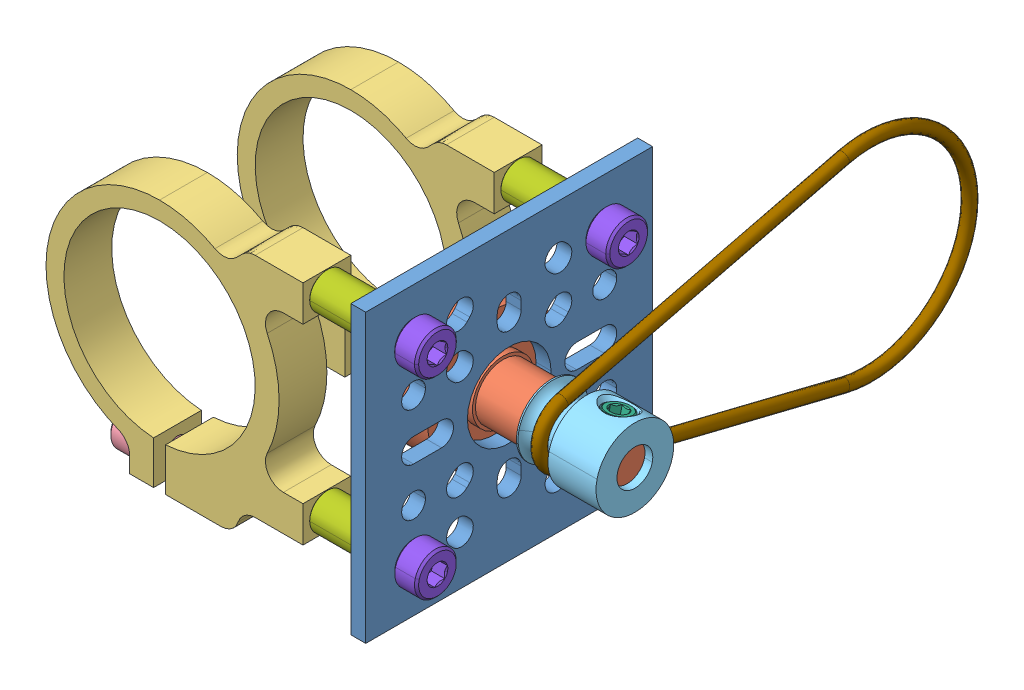
SolidWorks assembly Encoder2_Assembly, configuration Default. Lengths in mm.
Overall size (78.53 48 92).
23 component instances, 9 part files, 32 mates.
Components (placement in the parent):
- 1123-0048-0048-1: 1123-0048-0048 [Default] at (18.41 -24 21.5) size (2.5 48 48)
- 6127V1A360L.5 Non-Contacting Hall Effect-1: 6127V1A360L.5 Non-Contacting Hall Effect [Default] at origin size (35.77 22.23 22.23)
- 1400-0032-0032 assembly-1: 1400-0032-0032 assembly [Default] at (-32.0342 -9.2052 15.0483) x (0 -1 0) z (0 0 -1) size (42.19 43 8)
  - 1400-0032-0032 assembly.STEP-1: 1400-0032-0032 assembly.STEP [Default] at origin size (42.19 43 8)
    - 1400-0032-0032.STEP-1: 1400-0032-0032.STEP [Default] at (-9.2052 9.5558 -4.9517) size (42.17 43 8)
    - 2800-0004-0012_90128A207.STEP-1: 2800-0004-0012_90128A207.STEP [Default] at (10.4635 2.5558 -0.9517) x (0.999977 0 0.006769) z (0 -1 0) size (7 7 16.01)
- 1400-0032-0032 assembly-2: 1400-0032-0032 assembly [Default] at (-32.0342 -9.2052 -16.9517) x (0 -1 0) z (0 0 -1) size (42.19 43 8)
  - 1400-0032-0032 assembly.STEP-1: 1400-0032-0032 assembly.STEP [Default] at origin size (42.19 43 8)
    - 1400-0032-0032.STEP-1: 1400-0032-0032.STEP [Default] at (-9.2052 9.5558 -4.9517) size (42.17 43 8)
    - 2800-0004-0012_90128A207.STEP-1: 2800-0004-0012_90128A207.STEP [Default] at (10.4635 2.5558 -0.9517) x (0.999977 0 0.006769) z (0 -1 0) size (7 7 16.01)
- 3401-0006-0008 assembly-1: 3401-0006-0008 assembly [Default] at (9.8045 -37.374 -32.0723) x (0 -0.226049 -0.974116) z (1 0 0) size (13 13.01 14)
  - 3401-0006-0008 assembly.STEP-1: 3401-0006-0008 assembly.STEP [Default] at origin size (13 13.01 14)
    - 3401-0006-0008.STEP-1: 3401-0006-0008.STEP [Default] at (-39.6905 29.1567 8.1355) size (13 13.01 14)
    - 2806-0005-0004_91390A117.STEP-1: 2806-0005-0004_91390A117.STEP [Default] at (-39.6905 33.4996 4.1145) x (0.999377 0 0.035289) z (0 1 0) size (5.01 5.01 4.01)
- 1502-0006-0120-1: 1502-0006-0120 [Default] at (-11.59 16 16) x (0 1 0) z (0 0 1) size (5.95 12 5.95)
- 1502-0006-0120-2: 1502-0006-0120 [Default] at (-11.59 16 -16) x (0 1 0) z (0 0 1) size (5.95 12 5.95)
- 1502-0006-0120-3: 1502-0006-0120 [Default] at (-11.59 -16 16) x (0 1 0) z (0 0 1) size (5.95 12 5.95)
- 1502-0006-0120-4: 1502-0006-0120 [Default] at (-11.59 -16 -16) x (0 1 0) z (0 0 1) size (5.95 12 5.95)
- 2800-0004-0018-1: 2800-0004-0018 [Default] at (-21.09 16 16) x (0 0 1) z (-1 0 0) size (7 7 22.01)
- 2800-0004-0018-2: 2800-0004-0018 [Default] at (-21.09 -16 16) x (0 0.259369 0.965778) z (-1 0 0) size (7 7 22.01)
- 2800-0004-0018-3: 2800-0004-0018 [Default] at (-21.09 -16 -16) x (0 0 1) z (-1 0 0) size (7 7 22.01)
- 2800-0004-0018-4: 2800-0004-0018 [Default] at (-21.09 16 -16) x (0 0 1) z (-1 0 0) size (7 7 22.01)
- Round_Belt-1: Round_Belt [Default] at (6.94 0 0) x (0 0 -1) z (1 0 0) size (74 36 2)
Mates (geometry in assembly coordinates):
- Coincident2: coincident aligned: plane of 6127V1A360L.5 Non-Contacting Hall Effect-1 through (0 0 0) normal (0 0 1)
- Coincident3: coincident aligned: plane of 6127V1A360L.5 Non-Contacting Hall Effect-1 through (0 0 0) normal (0 1 0)
- Coincident4: coincident aligned: plane of 6127V1A360L.5 Non-Contacting Hall Effect-1 through (0 0 0) normal (1 0 0)
- Concentric1: concentric aligned: cylinder of 1123-0048-0048-1 through (4.41 0 0) axis (-1 0 0) radius 7; cylinder of 6127V1A360L.5 Non-Contacting Hall Effect-1 through (-16.64 0 0) axis (-1 0 0) radius 3.175
- Coincident5: coincident anti-aligned: plane of 1123-0048-0048-1 through (-5.59 24 -24) normal (-1 0 0); plane of 6127V1A360L.5 Non-Contacting Hall Effect-1 through (-5.59 11.115 0) normal (1 0 0)
- Parallel1: parallel aligned: plane of 1123-0048-0048-1 through (42.41 24 24) normal (0 0 1); plane of 1400-0032-0032 assembly-1/1400-0032-0032 assembly.STEP-1/1400-0032-0032.STEP-1 through (-41.59 0 20) normal (0 0 1)
- Parallel2: parallel aligned: plane of 1123-0048-0048-1 through (18.41 24 21.5) normal (0 1 0)
- Coincident9: coincident aligned: cylinder of 1123-0048-0048-1 through (4.41 16 16) axis (-1 0 0) radius 2; circle of 1400-0032-0032 assembly-1/1400-0032-0032 assembly.STEP-1/1400-0032-0032.STEP-1
- Distance1: distance = 12 mm anti-aligned: plane of 1123-0048-0048-1 through (-5.59 24 -24) normal (-1 0 0); plane of 1400-0032-0032 assembly-1/1400-0032-0032 assembly.STEP-1/1400-0032-0032.STEP-1 through (-17.59 13 12) normal (1 0 0)
- Concentric2: concentric aligned: cylinder of 1400-0032-0032 assembly-1/1400-0032-0032 assembly.STEP-1/1400-0032-0032.STEP-1 through (-41.59 0 12) axis (0 0 1) radius 16; cylinder of 1400-0032-0032 assembly-2/1400-0032-0032 assembly.STEP-1/1400-0032-0032.STEP-1 through (-41.59 0 -20) axis (0 0 1) radius 16
- Coincident11: coincident aligned: cylinder of 1123-0048-0048-1 through (4.41 16 -16) axis (-1 0 0) radius 2; circle of 1400-0032-0032 assembly-2/1400-0032-0032 assembly.STEP-1/1400-0032-0032.STEP-1
- Concentric3: concentric anti-aligned: cylinder of 6127V1A360L.5 Non-Contacting Hall Effect-1 through (-16.64 0 0) axis (-1 0 0) radius 3.175; cylinder of 3401-0006-0008 assembly-1/3401-0006-0008 assembly.STEP-1/3401-0006-0008.STEP-1 through (17.94 0 0) axis (1 0 0) radius 3
- Coincident12: coincident anti-aligned: plane of 6127V1A360L.5 Non-Contacting Hall Effect-1 through (3.94 3.175 0) normal (1 0 0); plane of 3401-0006-0008 assembly-1/3401-0006-0008 assembly.STEP-1/3401-0006-0008.STEP-1 through (3.94 0 0) normal (-1 0 0)
- Concentric4: concentric anti-aligned: cylinder of 1123-0048-0048-1 through (4.41 16 16) axis (-1 0 0) radius 2; cylinder of 1502-0006-0120-1 through (-17.59 16 16) axis (1 0 0) radius 2.975
- Concentric5: concentric anti-aligned: cylinder of 1123-0048-0048-1 through (4.41 16 -16) axis (-1 0 0) radius 2; cylinder of 1502-0006-0120-2 through (-17.59 16 -16) axis (1 0 0) radius 2.975
- Concentric6: concentric anti-aligned: cylinder of 1123-0048-0048-1 through (4.41 -16 -16) axis (-1 0 0) radius 2; cylinder of 1502-0006-0120-4 through (-17.59 -16 -16) axis (1 0 0) radius 2.975
- Concentric7: concentric anti-aligned: cylinder of 1123-0048-0048-1 through (4.41 -16 16) axis (-1 0 0) radius 2; cylinder of 1502-0006-0120-3 through (-17.59 -16 16) axis (1 0 0) radius 2.975
- Coincident13: coincident anti-aligned: plane of 1123-0048-0048-1 through (-5.59 24 -24) normal (-1 0 0); plane of 1502-0006-0120-1 through (-5.59 16 16) normal (1 0 0)
- Coincident14: coincident anti-aligned: plane of 1123-0048-0048-1 through (-5.59 24 -24) normal (-1 0 0); plane of 1502-0006-0120-2 through (-5.59 16 -16) normal (1 0 0)
- Coincident15: coincident anti-aligned: plane of 1123-0048-0048-1 through (-5.59 24 -24) normal (-1 0 0); plane of 1502-0006-0120-3 through (-5.59 -16 16) normal (1 0 0)
- Coincident16: coincident anti-aligned: plane of 1123-0048-0048-1 through (-5.59 24 -24) normal (-1 0 0); plane of 1502-0006-0120-4 through (-5.59 -16 -16) normal (1 0 0)
- Coincident17: coincident anti-aligned: plane of 1123-0048-0048-1 through (-3.09 24 21.5) normal (1 0 0); plane of 2800-0004-0018-1 through (-3.09 16 16) normal (-1 0 0)
- Concentric8: concentric aligned: cylinder of 1123-0048-0048-1 through (4.41 16 16) axis (-1 0 0) radius 2; cylinder of 2800-0004-0018-1 through (0.91 16 16) axis (-1 0 0) radius 3.5
- Concentric9: concentric aligned: cylinder of 1123-0048-0048-1 through (4.41 -16 16) axis (-1 0 0) radius 2; cylinder of 2800-0004-0018-2 through (0.91 -16 16) axis (-1 0 0) radius 3.5
- Coincident18: coincident anti-aligned: plane of 1123-0048-0048-1 through (-3.09 24 21.5) normal (1 0 0); plane of 2800-0004-0018-2 through (-3.09 -16 16) normal (-1 0 0)
- Coincident19: coincident anti-aligned: plane of 1123-0048-0048-1 through (-3.09 24 21.5) normal (1 0 0); plane of 2800-0004-0018-3 through (-3.09 -16 -16) normal (-1 0 0)
- Coincident20: coincident anti-aligned: plane of 1123-0048-0048-1 through (-3.09 24 21.5) normal (1 0 0); plane of 2800-0004-0018-4 through (-3.09 16 -16) normal (-1 0 0)
- Concentric10: concentric aligned: cylinder of 1123-0048-0048-1 through (4.41 16 -16) axis (-1 0 0) radius 2; cylinder of 2800-0004-0018-4 through (0.91 16 -16) axis (-1 0 0) radius 3.5
- Concentric11: concentric aligned: cylinder of 1123-0048-0048-1 through (4.41 -16 -16) axis (-1 0 0) radius 2; cylinder of 2800-0004-0018-3 through (0.91 -16 -16) axis (-1 0 0) radius 3.5
- Concentric12: concentric aligned: circle of 3401-0006-0008 assembly-1/3401-0006-0008 assembly.STEP-1/3401-0006-0008.STEP-1; circle of Round_Belt-1
- Coincident21: coincident aligned: circle of 3401-0006-0008 assembly-1/3401-0006-0008 assembly.STEP-1/3401-0006-0008.STEP-1; plane of Round_Belt-1 through (6.94 0 0) normal (1 0 0)
- Coincident22: coincident aligned: plane of Round_Belt-1 through (6.94 0 0) normal (0 1 0)
